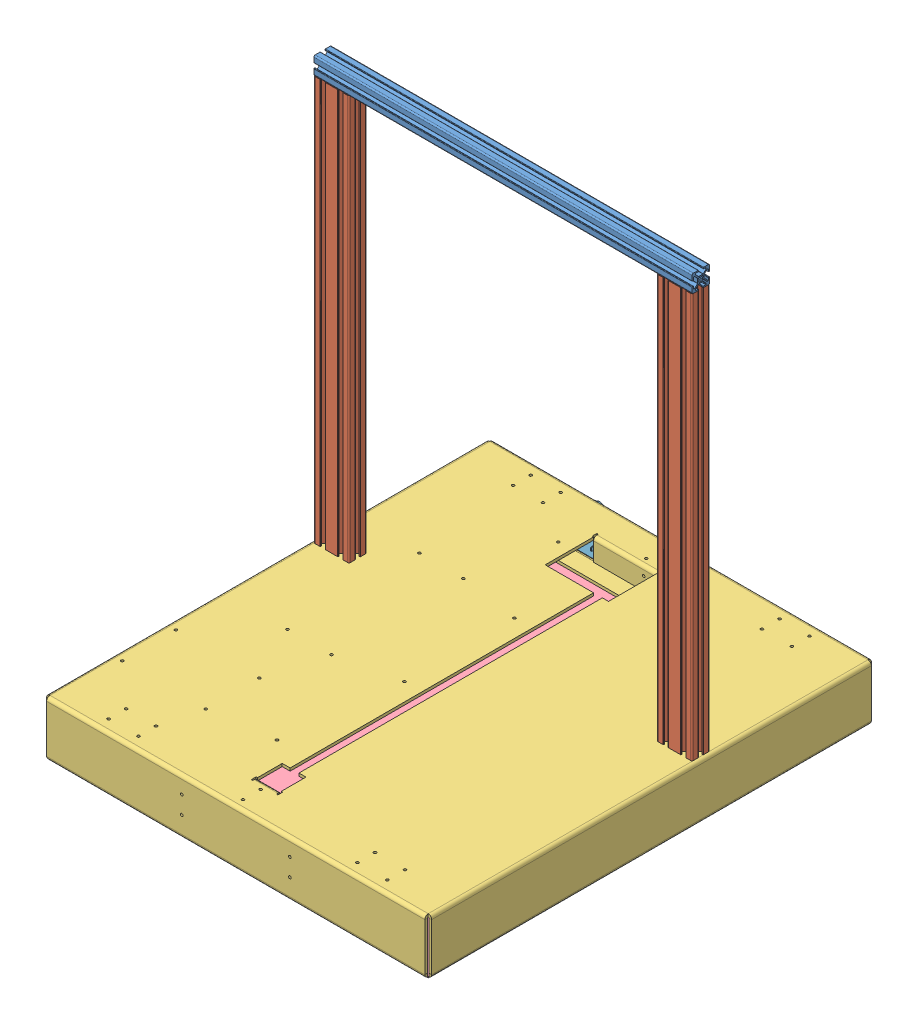
SolidWorks assembly Frame Assembly, configuration Default. Lengths in mm.
Overall size (437.82 543.39 517.28).
18 component instances, 9 part files, 15 mates.
Components (placement in the parent):
- Frame and Cover-1: Frame and Cover [Default] at (488.7599 -20.5544 105.3834) size (437.82 543.39 507.82)
  - TopCeiling-1: TopCeiling [20-2020-BLACK] at (-74.5195 587.4544 205.3802) x (0 0 -1) z (1 0 0) size (20 20 430)
  - UprightSides-1: UprightSides [20-2040-BLACK] at (-84.5195 117.4544 205.3802) x (1 0 0) z (0 -1 0) size (40 20 460)
  - UprightSides-2: UprightSides [20-2040-BLACK] at (-474.5195 117.4544 205.3802) x (1 0 0) z (0 -1 0) size (40 20 460)
  - printer_Cover-1: printer_Cover [Default] at (-81.1195 117.4544 131.1302) size (437.82 62.09 507.82)
  - bottom_Cover-1: bottom_Cover [Default] at (4575.451 55.3678 5402.6088) size (430 1.3 500)
- power switch-1: power switch [Standard] at (101.2109 67.9884 116.852) size (58.2 48.75 32.65)
- EinsyAssembly_StandOff-1: EinsyAssembly_StandOff [Default] at (-6.2482 152.6016 450.1588) x (1 0 0) z (0 -1 0) size (108.28 71 27.59)
  - Einsy_Rambo-1: Einsy_Rambo [Default] at (14.9676 86.704 68.4713) size (108.28 71 21.5)
  - standOffs-1: standOffs [Default] at (92.9775 34.4902 66.8766) x (1 0 0) z (0 -1 0) size (5 8 5)
  - standOffs-3: standOffs [Default] at (92.6031 96.0937 66.8766) x (0 1 0) z (1 0 0) size (5 8 5)
  - standOffs-4: standOffs [Default] at (-2.0225 34.4902 66.8766) x (1 0 0) z (0 -1 0) size (5 8 5)
  - standOffs-5: standOffs [Default] at (-2.0225 95.4902 66.8766) x (1 0 0) z (0 -1 0) size (5 8 5)
- 24V15A power supply-5: 24V15A power supply [Standard] at (78.7404 93.725 345.2636) x (0 0 -1) z (0 -1 0) size (215 113 50)
- wireClamp_25-6: wireClamp_25 [Default] at (150.0789 96.5825 393.0636) x (-1 0 0) z (0 0 1) size (41.15 12.95 25.4)
- wireClamp_25-7: wireClamp_25 [Default] at (150.0789 96.5825 268.0636) x (-1 0 0) z (0 0 1) size (41.15 12.95 25.4)
- wireClamp_25-8: wireClamp_25 [Default] at (169.9404 96.5825 513.6021) x (0 0 -1) z (-1 0 0) size (41.15 12.95 25.4)
- wireClamp_25-9: wireClamp_25 [Default] at (100.0789 96.5825 168.0636) x (-1 0 0) z (0 0 1) size (41.15 12.95 25.4)
Mates (geometry in assembly coordinates):
- Coincident10: coincident anti-aligned: plane of Frame and Cover-1/printer_Cover-1 through (407.6404 93.725 236.5136) normal (0 -1 0); plane of EinsyAssembly_StandOff-1/standOffs-3 through (86.2404 93.725 545.7636) normal (0 1 0)
- Coincident12: coincident anti-aligned: plane of Frame and Cover-1/printer_Cover-1 through (407.6404 96.9 116.852) normal (0 0 -1); plane of power switch-1 through (101.2109 67.9884 116.852) normal (0 0 1)
- Concentric1: concentric anti-aligned: circle of Frame and Cover-1/printer_Cover-1; circle of power switch-1
- Coincident14: coincident anti-aligned: circle of Frame and Cover-1/printer_Cover-1; circle of EinsyAssembly_StandOff-1/standOffs-5
- Coincident15: coincident anti-aligned: plane of Frame and Cover-1/printer_Cover-1 through (407.6404 93.725 236.5136) normal (0 -1 0); plane of 24V15A power supply-5 through (78.7404 93.725 345.2636) normal (0 1 0)
- Concentric2: concentric aligned: circle of Frame and Cover-1/printer_Cover-1; circle of 24V15A power supply-5
- Concentric3: concentric aligned: circle of Frame and Cover-1/printer_Cover-1; circle of 24V15A power supply-5
- Coincident16: coincident anti-aligned: plane of Frame and Cover-1/printer_Cover-1 through (407.6404 93.725 236.5136) normal (0 -1 0); plane of wireClamp_25-8 through (144.5404 93.725 521.5396) normal (0 1 0)
- Coincident17: coincident anti-aligned: plane of Frame and Cover-1/printer_Cover-1 through (407.6404 93.725 236.5136) normal (0 -1 0); plane of wireClamp_25-6 through (158.0164 93.725 418.4636) normal (0 1 0)
- Coincident18: coincident anti-aligned: plane of Frame and Cover-1/printer_Cover-1 through (407.6404 93.725 236.5136) normal (0 -1 0); plane of wireClamp_25-7 through (158.0164 93.725 293.4636) normal (0 1 0)
- Coincident19: coincident anti-aligned: plane of Frame and Cover-1/printer_Cover-1 through (407.6404 93.725 236.5136) normal (0 -1 0); plane of wireClamp_25-9 through (108.0164 93.725 193.4636) normal (0 1 0)
- Coincident29: coincident anti-aligned: circle of Frame and Cover-1/printer_Cover-1; circle of wireClamp_25-6
- Coincident30: coincident anti-aligned: circle of Frame and Cover-1/printer_Cover-1; circle of wireClamp_25-8
- Coincident31: coincident anti-aligned: circle of Frame and Cover-1/printer_Cover-1; circle of wireClamp_25-7
- Coincident32: coincident anti-aligned: circle of Frame and Cover-1/printer_Cover-1; circle of wireClamp_25-9
